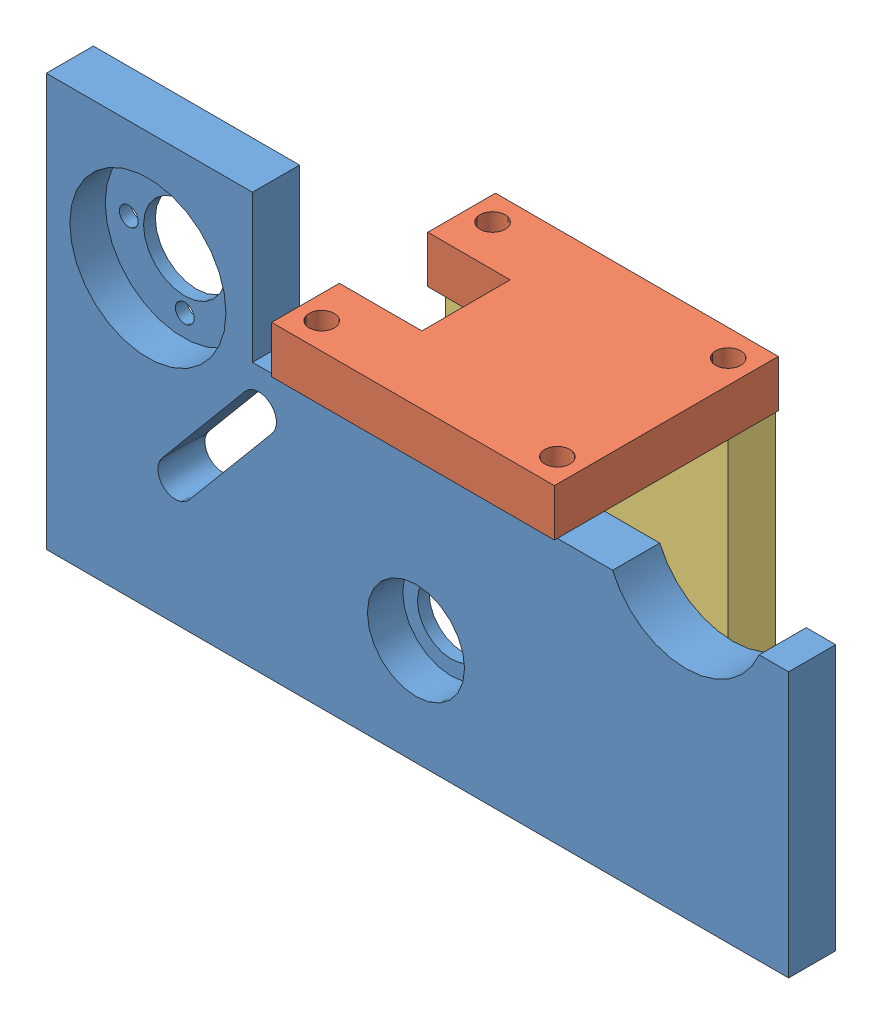
SolidWorks assembly Assemblage support opti, configuration Défaut. Lengths in mm.
Overall size (126 70 38).
3 component instances, 3 part files, 6 mates.
Components (placement in the parent):
- support principal-1: support principal [Défaut] at (-6.4514 -7.9304 125) size (126 70 8)
- dessus support-1: dessus support [Défaut] at (2.913 4.7406 114.5) x (-1 0 0) z (0 1 0) size (48 38 8)
- côté support-1: côté support [Défaut] at (2.913 -17.7594 96) size (48 45 8)
Mates (geometry in assembly coordinates):
- Coïncidente2: coincident anti-aligned: plane of support principal-1 through (66.163 4.7406 133) normal (0 1 0); plane of dessus support-1 through (2.913 4.7406 114.5) normal (0 -1 0)
- Coïncidente12: coincident anti-aligned: plane of dessus support-1 through (2.913 4.7406 114.5) normal (0 -1 0); plane of côté support-1 through (-21.087 4.7406 104) normal (0 1 0)
- Coaxiale1: concentric anti-aligned: circle of dessus support-1; circle of côté support-1
- Coaxiale2: concentric anti-aligned: circle of support principal-1; circle of dessus support-1
- Coaxiale3: concentric anti-aligned: circle of support principal-1; circle of dessus support-1
- Coaxiale4: concentric anti-aligned: circle of dessus support-1; circle of côté support-1
